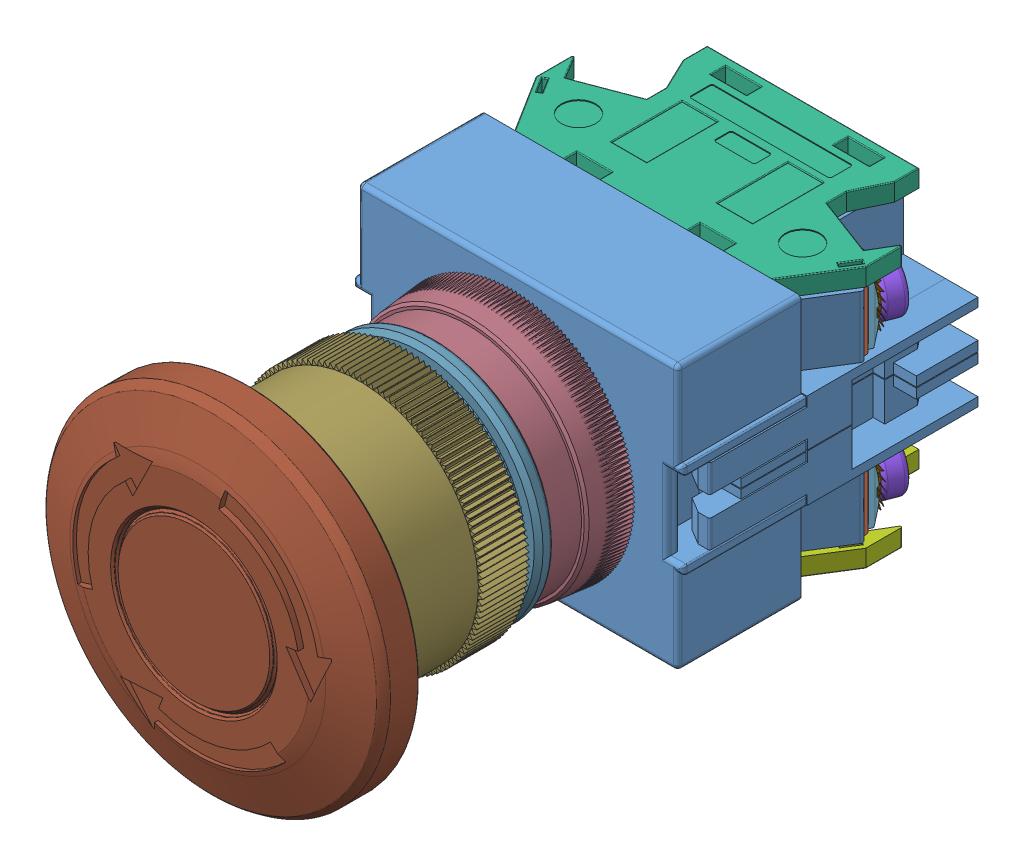
SolidWorks assembly MONTAGEM FINAL, configuration Valor predeterminado. Lengths in mm.
Overall size (53.77 53.77 70.49).
27 component instances, 14 part files, 0 mates.
Components (placement in the parent):
- corpo1-1: corpo1 [Valor predeterminado] at origin size (37.4 30 52.27)
- TERMINAL FIXO-1: TERMINAL FIXO [Valor predeterminado] at (-17.4785 5.4547 -5.6252) x (0 1 0) z (-0.936672 0 0.350207) size (6.7 2.25 8.2)
- TERMINAL FIXO-2: TERMINAL FIXO [Valor predeterminado] at (17.4738 12.1798 -5.616) x (0 -1 0) z (0.93358 0 0.358368) size (6.7 2.25 8.2)
- TERMINAL FIXO-4: TERMINAL FIXO [Valor predeterminado] at (17.473 -5.4807 -5.6271) x (0 -1 0) z (0.93358 0 0.358368) size (6.7 2.25 8.2)
- TERMINAL FIXO-5: TERMINAL FIXO [Valor predeterminado] at (-17.462 -12.1795 -5.6261) x (0 1 0) z (-0.936672 0 0.350207) size (6.7 2.25 8.2)
- MOLA2-1: MOLA2 [Valor predeterminado] at (-0.0193 5.3596 -18.1661) size (2.5 2.89 10.2)
- MOLA2-2: MOLA2 [Valor predeterminado] at (-0.0225 -5.3272 -18.166) size (2.5 2.89 10.2)
- MOLA-1: MOLA [Valor predeterminado] at (0.1318 0.0353 8.3646) x (1 0 0) z (0 -1 0) size (18.9 29.8 19.4)
- washer-1: washer [Valor predeterminado] at (-14.3403 -8.8366 -8.8883) x (-0.350207 0 -0.936672) z (0.936672 0 -0.350207) size (1.12 6.65 6.8)
- washer-2: washer [Valor predeterminado] at (14.4001 8.7838 -9.0181) x (0.350207 0 -0.936672) z (0.936672 0 0.350207) size (1.12 6.65 6.8)
- washer-3: washer [Valor predeterminado] at (-14.3775 8.7959 -8.9721) x (-0.350207 0 -0.936672) z (0.936672 0 -0.350207) size (1.12 6.65 6.8)
- washer-4: washer [Valor predeterminado] at (14.4115 -8.8453 -9.0338) x (0.350207 0 -0.936672) z (0.936672 0 0.350207) size (1.12 6.65 6.8)
- COVER-VERDE-1: COVER-VERDE [Valor predeterminado] at (0.0015 -58.6356 0.0118) size (37.4 7 19.4)
- COVER-VERMELHO-3: COVER-VERMELHO [Valor predeterminado] at (0.0018 58.4837 0.0125) x (-1 0 0) z (0 0 1) size (37.4 7 19.4)
- screw-1: screw [Valor predeterminado] at (16.0259 8.7795 -12.9551) x (0.93358 0 0.358368) z (-0.358368 0 0.93358) size (5.54 5.54 7.5)
- screw-2: screw [Valor predeterminado] at (-15.6991 8.7506 -13.0583) x (0.936672 0 -0.350207) z (0.350207 0 0.936672) size (5.54 5.54 7.5)
- screw-3: screw [Valor predeterminado] at (-15.6791 -8.8081 -13.0535) x (0.939693 0 -0.34202) z (0.34202 0 0.939693) size (5.54 5.54 7.5)
- screw-4: screw [Valor predeterminado] at (16.028 -8.8132 -12.9573) x (0.93358 0 0.358368) z (-0.358368 0 0.93358) size (5.54 5.54 7.5)
- WASHER ESTRELADA-1: WASHER ESTRELADA [Valor predeterminado] at (15.1355 8.7808 -10.6344) x (0.936672 0 0.350207) z (-0.350207 0 0.936672) size (7.01 7.01 1.04)
- WASHER ESTRELADA-2: WASHER ESTRELADA [Valor predeterminado] at (-14.8296 8.6127 -10.7013) x (0.93358 0 -0.358368) z (0.358368 0 0.93358) size (7.01 7.01 1.04)
- WASHER ESTRELADA-3: WASHER ESTRELADA [Valor predeterminado] at (15.1184 -8.8527 -10.6478) x (0.936672 0 0.350207) z (-0.350207 0 0.936672) size (7.01 7.01 1.04)
- WASHER ESTRELADA-4: WASHER ESTRELADA [Valor predeterminado] at (-14.9472 -8.9611 -10.6755) x (0.93358 0 -0.358368) z (0.358368 0 0.93358) size (7.01 7.01 1.04)
- HASTE-1: HASTE [Valor predeterminado] at (0.0234 0.0366 3.7711) size (19.82 19.82 42)
- CHAVE STOP-1: CHAVE STOP [Valor predeterminado] at (-0.0172 0.059 37.991) x (-0.48481 -0.87462 0) z (0 0 1) size (39.56 39.56 13)
- PORCA-CROMO-1: PORCA-CROMO [Valor predeterminado] at (-0.025 0.0246 26.6451) size (27.98 27.99 14.01)
- CONTRA-PORCA-1: CONTRA-PORCA [Valor predeterminado] at (0.0346 0.0248 14.7485) x (1 0 0) z (0 -1 0) size (28 8.41 28)
- ANEL RETAINER-1: ANEL RETAINER [Valor predeterminado] at (-0.025 0.0044 26.2994) x (1 0 0) z (0 0 -1) size (27 27 2.45)
